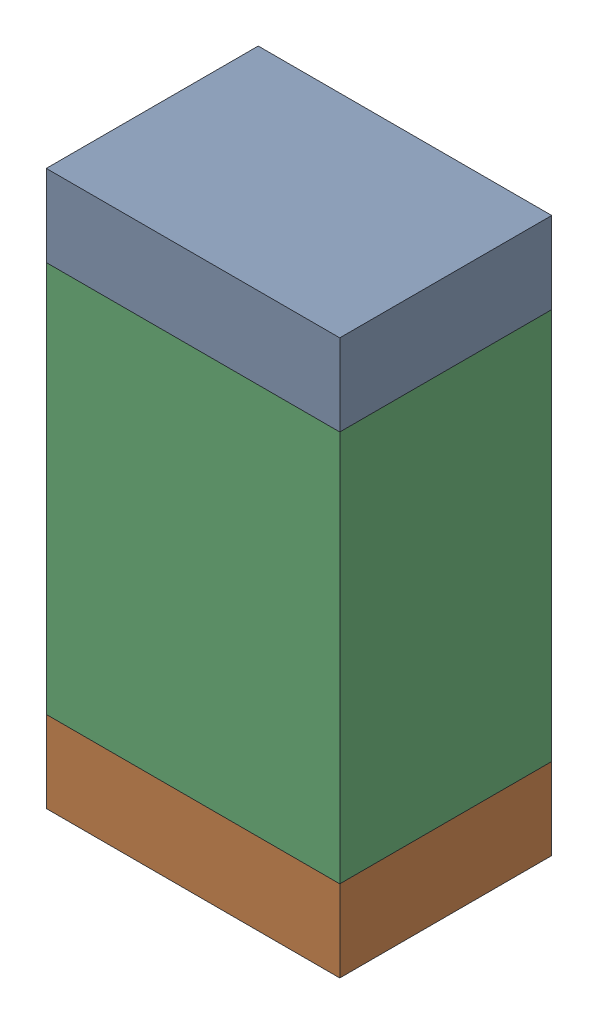
SolidWorks assembly C8, configuration Default. Lengths in mm.
Overall size (1.8 3.4 1.3).
6 component instances, 2 part files, 0 mates.
Components (placement in the parent):
- 8284095360-1: 8284095360 [Default] at (159 75.95 -2.9914) size (1.8 0.5 1.3)
  - Extruded_3-1: Extruded_3 [Default] at origin size (1.8 0.5 1.3)
- 8284095360-2: 8284095360 [Default] at (159 73.05 -2.9914) size (1.8 0.5 1.3)
  - Extruded_3-1: Extruded_3 [Default] at origin size (1.8 0.5 1.3)
- 8284081680-1: 8284081680 [Default] at (159 74.5 -2.9914) size (1.8 2.4 1.3)
  - Extruded_6-1: Extruded_6 [Default] at origin size (1.8 2.4 1.3)
